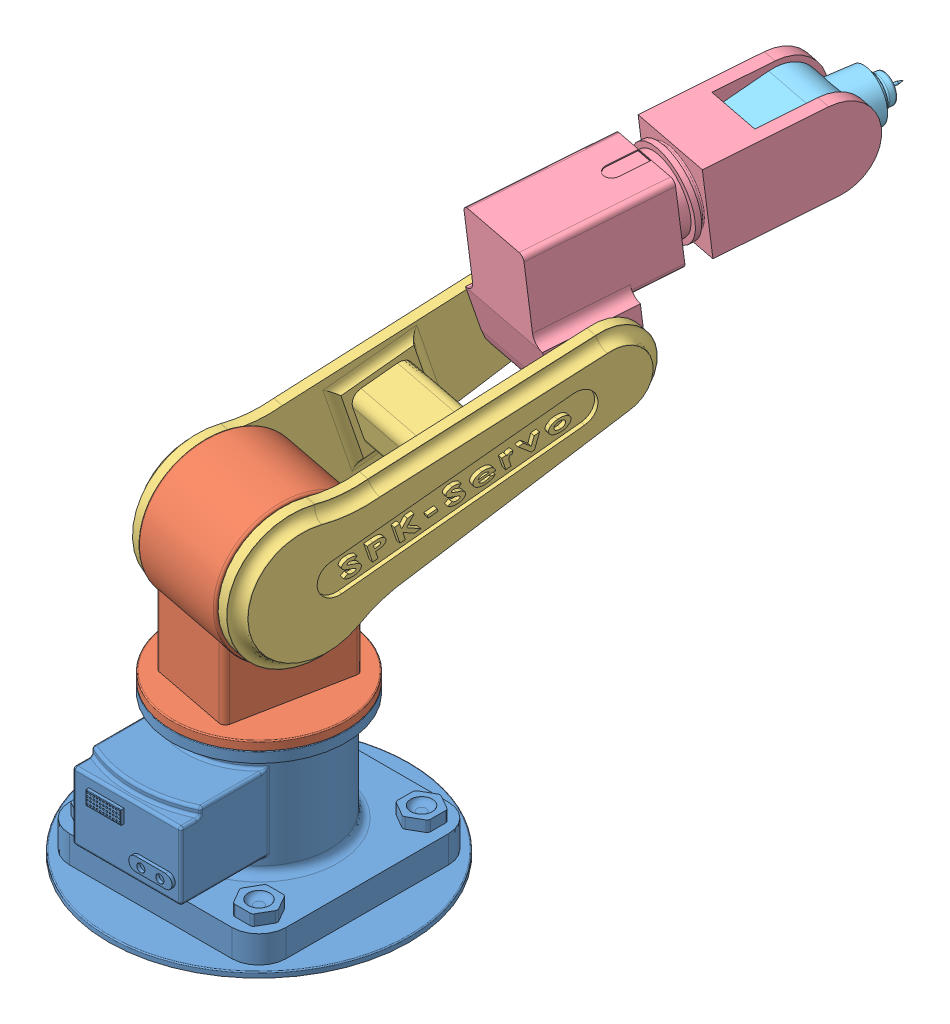
SolidWorks assembly ROBOT4, configuration Default. Lengths in mm.
Overall size (555 914.86 1284.84).
5 component instances, 5 part files, 8 mates.
Components (placement in the parent):
- Base-1: Base [Default] at (143.8317 162.8405 457.2494) size (555 280 555)
- Link1-1: Link1 [Default] at (143.8317 312.8405 457.2494) x (0.191485 0 -0.981495) z (0.981495 0 0.191485) size (320 466 320)
- Link2-1: Link2 [Default] at (143.8317 648.8405 457.2494) x (-0.981495 0 -0.191485) z (0.056699 -0.955156 -0.290623) size (260.14 700 250)
- Link3-1: Link3 [Default] at (235.2809 796.8916 -11.4914) x (-0.981495 0 -0.191485) z (0.021256 -0.99382 -0.108951) size (180 555 365)
- Link4-1: Link4 [Default] at (330.3283 989.6031 -498.6749) x (0.007596 -0.999213 -0.038937) z (-0.981495 0 -0.191485) size (130 266.16 100)
Mates (geometry in assembly coordinates):
- Concentric1: concentric anti-aligned: cylinder of Base-1 through (143.8317 312.8405 457.2494) axis (0 1 0) radius 100; cylinder of Link1-1 through (143.8317 432.8405 457.2494) axis (0 -1 0) radius 100
- Coincident1: coincident anti-aligned: plane of Base-1 through (143.8317 432.8405 457.2494) normal (0 1 0); plane of Link1-1 through (143.8317 432.8405 457.2494) normal (0 -1 0)
- Concentric2: concentric anti-aligned: cylinder of Link1-1 through (232.1663 648.8405 474.4831) axis (-0.981495 0 -0.191485) radius 75; cylinder of Link2-1 through (55.4971 648.8405 440.0157) axis (0.981495 0 0.191485) radius 75
- Coincident2: coincident anti-aligned: plane of Link1-1 through (55.4971 648.8405 440.0157) normal (-0.981495 0 -0.191485); plane of Link2-1 through (62.7969 971.5919 402.599) normal (0.981495 0 0.191485)
- Concentric3: concentric aligned: cylinder of Link2-1 through (146.9463 796.8916 -28.7251) axis (0.981495 0 0.191485) radius 50; cylinder of Link3-1 through (146.9463 796.8916 -28.7251) axis (0.981495 0 0.191485) radius 50
- Coincident3: coincident anti-aligned: plane of Link2-1 through (239.4661 971.5919 437.0664) normal (-0.981495 0 -0.191485); plane of Link3-1 through (304.3577 931.5601 104.4517) normal (0.981495 0 0.191485)
- Concentric4: concentric anti-aligned: cylinder of Link3-1 through (356.4429 984.8425 -371.4139) axis (-0.981495 0 -0.191485) radius 50; cylinder of Link4-1 through (258.2934 984.8425 -390.5625) axis (0.981495 0 0.191485) radius 50
- Coincident4: coincident anti-aligned: plane of Link3-1 through (356.4429 984.8425 -371.4139) normal (-0.981495 0 -0.191485); plane of Link4-1 through (356.4429 984.8425 -371.4139) normal (0.981495 0 0.191485)
